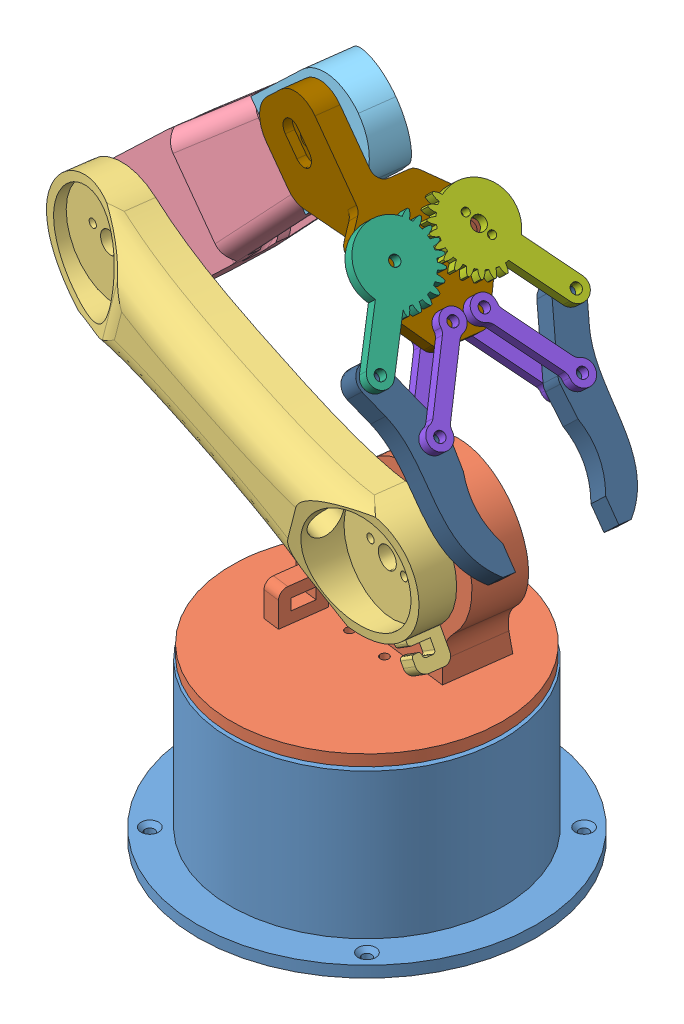
SolidWorks assembly Robotic Arm URDF, configuration Default. Lengths in mm.
Overall size (225.3 237.71 124.49).
16 component instances, 11 part files, 15 mates.
Components (placement in the parent):
- Base-1: Base [Default] x (0 0 -1) z (1 0 0) size (121.25 56 121.25)
- Waist-1: Waist [Default] at (0 57 0) x (-0.128933 0 0.991653) z (-0.991653 0 -0.128933) size (97 64.78 97)
- Arm 01-1: Arm 01 [Default] at (14.0344 97.2765 0.0096) x (0.2739 0.961099 0.035612) z (-0.128933 0 0.991653) size (54.87 166.68 26.36)
- Arm 02 v3-1: Arm 02 v3 [Default] at (-74.7258 154.4027 -16.7746) x (-0.684358 0.723697 -0.088979) z (0.128933 0 -0.991653) size (38.57 115 28.32)
- Arm 03-1: Arm 03 [Default] at (-33.0125 193.4188 -16.8975) x (-0.684358 0.723697 -0.088979) z (0.128933 0 -0.991653) size (33 46 28)
- Gripper Assembly-1: Gripper Assembly [Default] at (-22.0448 228.4706 -7.9356) x (0.128933 0 -0.991653) z (0.684358 -0.723697 0.088979) size (98.22 36.05 139.41)
  - gear1-1: gear1 [Default] at (-22.9056 12.6028 63.2843) x (-0.581668 0 0.813426) z (-0.813426 0 -0.581668) size (49.29 4 26.63)
  - gear2-1: gear2 [Default] at (5.149 12.6028 46.1292) x (-0.467421 0 -0.884035) z (0.884035 0 -0.467421) size (49.02 4 26.63)
  - grip link 1-1: grip link 1 [Default] at (-26.7426 0.1028 100.5029) x (0.571471 0 -0.820623) z (0.820623 0 0.571471) size (39 4 8)
  - Gripper base-1: Gripper base [Default] at (-22.027 4.1028 80.0636) size (44.4 28 77)
  - grip link 1-2: grip link 1 [Default] at (18.9346 0.1028 100.3298) x (-0.579406 0 -0.815039) z (0.815039 0 -0.579406) size (39 4 8)
  - Gripper 1-1: Gripper 1 [Default] at (25.0683 4.1028 73.5645) x (0 1 0) z (0.39713 0 -0.917762) size (8.5 22.22 65.31)
  - Gripper 1-2: Gripper 1 [Default] at (-32.1279 12.6028 73.5771) x (0 -1 0) z (-0.371396 0 -0.928475) size (8.5 22.22 65.31)
  - Servo Motor Micro  9g-1: Servo Motor Micro  9g [Default] at (4.773 -19.4472 55.0636) x (-1 0 0) z (0 0 -1) size (32.6 29.9 12.4)
  - grip link 1-3: grip link 1 [Default] at (18.9346 12.6028 100.3298) x (-0.579406 0 -0.815039) z (0.815039 0 -0.579406) size (39 4 8)
  - grip link 1-4: grip link 1 [Default] at (-26.7426 16.6028 100.5029) x (0.571471 0 -0.820623) z (-0.820623 0 -0.571471) size (39 4 8)
Mates (geometry in assembly coordinates):
- Concentric5: concentric aligned: cylinder of Base-1 through (0 56 0) axis (0 -1 0) radius 49; cylinder of Waist-1 through (0 61 0) axis (0 -1 0) radius 48.5
- Distance1: distance = 1 mm anti-aligned: plane of Base-1 through (0 56 0) normal (0 1 0); plane of Waist-1 through (0 57 0) normal (0 -1 0)
- Concentric16: concentric aligned: cylinder of Waist-1 through (20.0557 97.2765 -46.3016) axis (-0.128933 0 0.991653) radius 9; cylinder of Arm 01-1 through (14.0345 97.2765 0.0086) axis (-0.128933 0 0.991653) radius 3.75
- Distance2: distance = 2.2 mm anti-aligned: plane of Arm 01-1 through (14.0344 97.2765 0.0096) normal (0.128933 0 -0.991653); plane of Waist-1 through (0.5157 57 -3.9666) normal (-0.128933 0 0.991653)
- Concentric18: concentric aligned: cylinder of Arm 03-1 through (-14.7232 212.7421 -0.4017) axis (0.128933 0 -0.991653) radius 6.5; cylinder of Gripper Assembly-1/Gripper base-1 through (-16.7217 212.7421 14.969) axis (0.128933 0 -0.991653) radius 2.5
- Distance4: distance = 1.5 mm anti-aligned: plane of Arm 03-1 through (9.4865 213.2232 2.746) normal (-0.128933 0 0.991653); plane of Gripper Assembly-1/Gripper base-1 through (10.8708 205.7587 4.4387) normal (0.128933 0 -0.991653)
- Concentric19: concentric anti-aligned: cylinder of Arm 01-1 through (-100.3346 130.4211 -14.8615) axis (-0.128933 0 0.991653) radius 3.75; cylinder of Arm 02 v3-1 through (-99.9222 130.4211 -18.0338) axis (0.128933 0 -0.991653) radius 9
- Distance5: distance = 3.2 mm anti-aligned: plane of Arm 01-1 through (14.0344 97.2765 0.0096) normal (0.128933 0 -0.991653); plane of Arm 02 v3-1 through (-104.4075 126.1079 -18.617) normal (-0.128933 0 0.991653)
- Concentric20: concentric aligned: cylinder of Waist-1 through (20.0557 97.2765 -46.3016) axis (-0.128933 0 0.991653) radius 9; cylinder of Arm 01-1 through (14.0345 97.2765 0.0086) axis (-0.128933 0 0.991653) radius 3.75
- Distance7: distance = 1.85 mm anti-aligned: plane of Arm 03-1 through (-33.0125 193.4188 -16.8975) normal (-0.717657 -0.690118 -0.093309); plane of Arm 02 v3-1 through (-35.2546 192.3592 -11.6427) normal (0.717657 0.690118 0.093309)
- Concentric21: concentric anti-aligned: cylinder of Arm 02 v3-1 through (-32.3537 187.1434 -16.8118) axis (0.717657 0.690118 0.093309) radius 6.5; cylinder of Arm 03-1 through (-20.9279 198.1308 -15.3262) axis (-0.717657 -0.690118 -0.093309) radius 2.5
- Concentric23: concentric: cylinder of Base-1 through (0 4 0) axis (0 -1 0) radius 60.625
- Coincident41: coincident: plane of Base-1 through (0 0 0) normal (0 -1 0)
- Coincident42: coincident anti-aligned: plane of Base-1 through (0 0 0) normal (0 -1 0)
- Coincident43: coincident anti-aligned: plane of Base-1 through (0 0 0) normal (0 0 -1)
